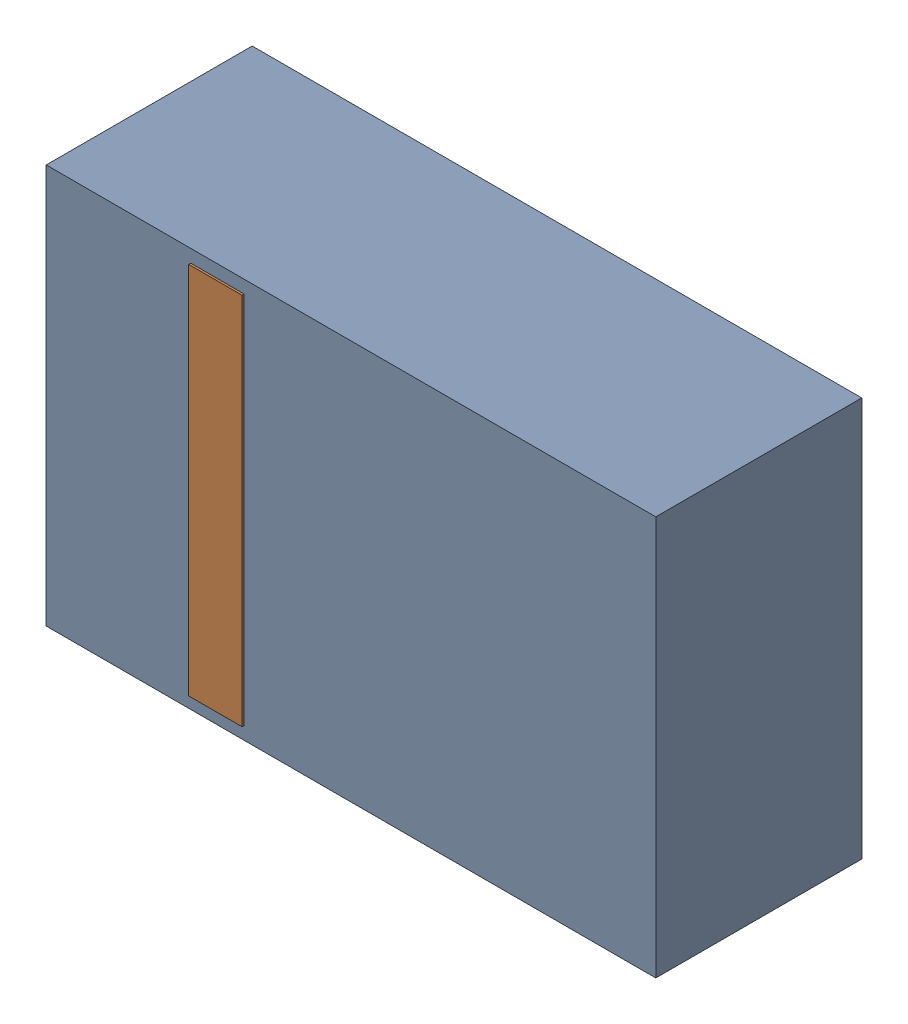
SolidWorks assembly D21, configuration Default. Lengths in mm.
Overall size (2.9 1.9 0.99).
4 component instances, 2 part files, 0 mates.
Components (placement in the parent):
- 905269392-1: 905269392 [Default] at (141.478 61.341 0) size (2.9 1.9 0.98)
  - Extruded_5-1: Extruded_5 [Default] at origin size (2.9 1.9 0.98)
- 905269800-1: 905269800 [Default] at (140.843 61.341 0.95) size (0.25 1.78 0.04)
  - Extruded_6-1: Extruded_6 [Default] at origin size (0.25 1.78 0.04)
